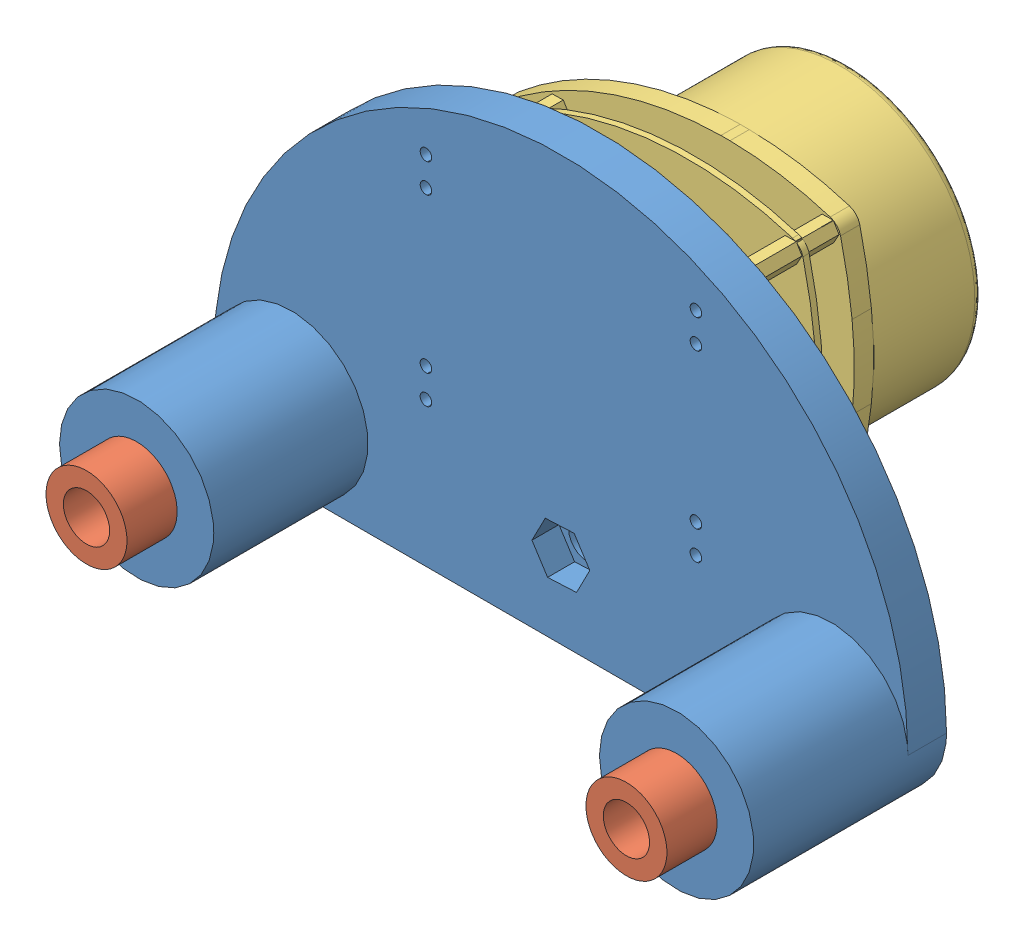
SolidWorks assembly ROCO318 RPLIDAR, configuration Default. Lengths in mm.
Overall size (180.03 110.05 120.7).
6 component instances, 3 part files, 9 mates.
Components (placement in the parent):
- ROCO318 extruded-1: ROCO318 extruded [Default] at (-86.0375 -1.7194 893) x (1 -0.000253 0) z (0 0 1) size (180 110 50)
- BALL BEARING-2: BALL BEARING [Default] at (-70 0 896) size (21 21 30)
- BALL BEARING-3: BALL BEARING [Default] at (-70 0 926) size (21 21 30)
- BALL BEARING-4: BALL BEARING [Default] at (70 0 896) size (21 21 30)
- BALL BEARING-5: BALL BEARING [Default] at (70 0 926) size (21 21 30)
- rplidar_main-2: rplidar_main [По умолчанию] at (-7.6108 45.4083 868.4) x (-1 0 0) z (0 -1 0) size (98.5 57.7 70.02)
Mates (geometry in assembly coordinates):
- Coincident8: coincident anti-aligned: plane of ROCO318 extruded-1 through (-70 0 896) normal (0 0 1); plane of BALL BEARING-2 through (-70 0 896) normal (0 0 -1)
- Concentric4: concentric aligned: cylinder of ROCO318 extruded-1 through (-70 0 903) axis (0 0 -1) radius 10.5; cylinder of BALL BEARING-2 through (-70 0 926) axis (0 0 -1) radius 10.5
- Coincident9: coincident anti-aligned: plane of BALL BEARING-2 through (-70 0 926) normal (0 0 1); plane of BALL BEARING-3 through (-70 0 926) normal (0 0 -1)
- Concentric5: concentric aligned: cylinder of ROCO318 extruded-1 through (-70 0 903) axis (0 0 -1) radius 10.5; cylinder of BALL BEARING-3 through (-70 0 956) axis (0 0 -1) radius 10.5
- Coincident10: coincident anti-aligned: plane of ROCO318 extruded-1 through (70 0 896) normal (0 0 1); plane of BALL BEARING-4 through (70 0 896) normal (0 0 -1)
- Concentric6: concentric aligned: cylinder of ROCO318 extruded-1 through (70 0 903) axis (0 0 -1) radius 10.5; cylinder of BALL BEARING-4 through (70 0 926) axis (0 0 -1) radius 10.5
- Coincident11: coincident anti-aligned: plane of BALL BEARING-4 through (70 0 926) normal (0 0 1); plane of BALL BEARING-5 through (70 0 926) normal (0 0 -1)
- Concentric7: concentric aligned: cylinder of ROCO318 extruded-1 through (70 0 903) axis (0 0 -1) radius 10.5; cylinder of BALL BEARING-5 through (70 0 956) axis (0 0 -1) radius 10.5
- Coincident14: coincident aligned: circle of ROCO318 extruded-1; plane of rplidar_main-2 through (-7.6108 45.4083 893) normal (0 0 1)
